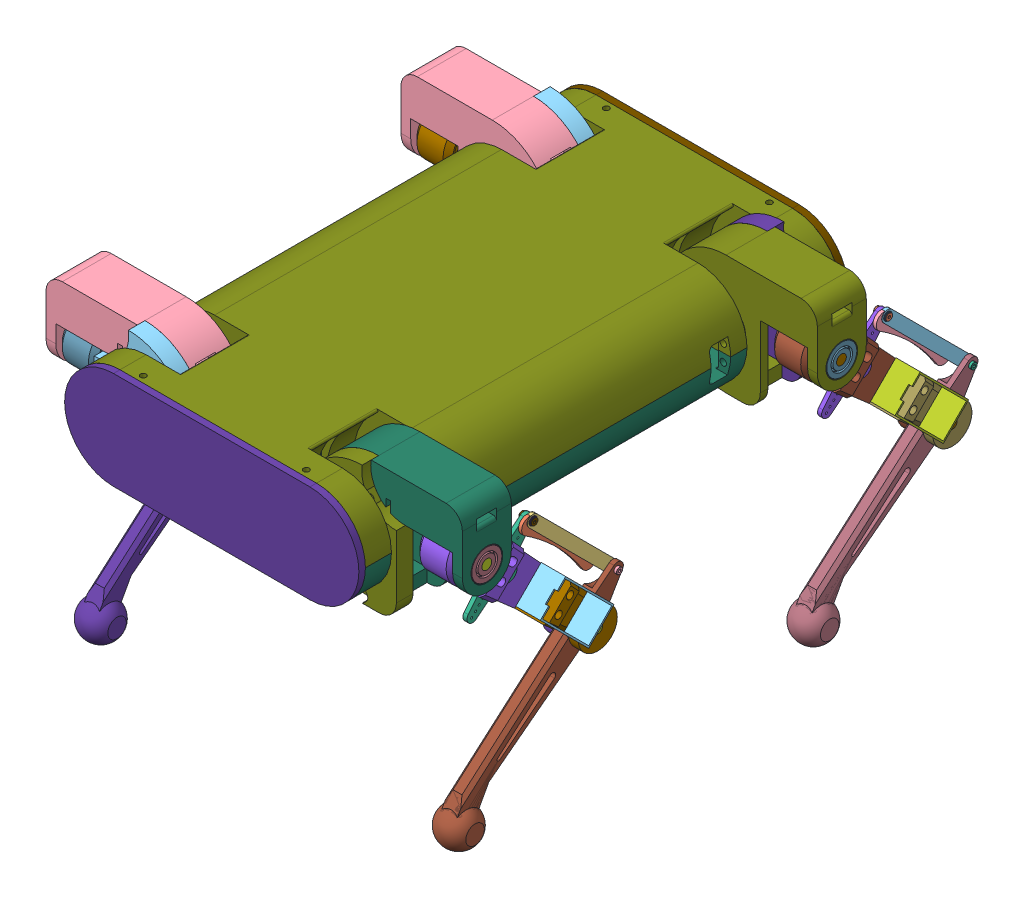
SolidWorks assembly Design, configuration Default. Lengths in mm.
Overall size (296.42 194.28 356.27).
132 component instances, 80 part files, 0 mates.
Components (placement in the parent):
- Design.STEP-1: Design.STEP [Default] at origin size (296.42 194.28 356.27)
  - legs.STEP-1: legs.STEP [Default] at origin size (296.42 194.28 346.24)
    - leg1.STEP-1: leg1.STEP [Default] at (-120.6897 -147.7213 110.0971) x (0 0 -1) z (1 0 0) size (128.74 194.28 113.16)
      - shoulder_joint.STEP-1: shoulder_joint.STEP [Default] at (0.6897 0.2213 10.9029) size (46.01 73.28 92.64)
        - Servo_00.STEP-1: Servo_00.STEP [Default] at (83.81 147 87) size (21 21 5.5)
          - Servo_00_horn.STEP-1: Servo_00_horn.STEP [Default] at (-145.7499 2.8989 -75.1177) x (-1 0 0) z (0 0 -1) size (21 21 5.5)
          - Servo_00-0.STEP-1: Servo_00-0.STEP [Default] at origin
        - Bearing 19mm.STEP-1: Bearing 19mm.STEP [Default] at (83.8 146.8 77.1) size (19 19 6)
        - Shaft 8mm.STEP-1: Shaft 8mm.STEP [Default] at (-17.7971 -1.7 -3.6029) x (0 0 -1) z (1 0 0) size (8 8 18)
        - shoulder_joint-1.STEP-1: shoulder_joint-1.STEP [Default] at origin size (30 73.28 92.64)
        - shoulder_joint-2.STEP-1: shoulder_joint-2.STEP [Default] at origin size (10.19 73.28 57.64)
      - upper_joint.STEP-1: upper_joint.STEP [Default] at origin size (112.4 102 49.52)
        - Servo_04_link.STEP-1: Servo_04_link.STEP [Default] at (84.861 148.6857 92.0002) size (55.54 55.54 12)
          - Bearing 5mm.STEP-1: Bearing 5mm.STEP [Default] at (-39.4979 -6.7113 -81.5973) size (5 5 1.32)
          - screw_nut M2 L60.STEP-1: screw_nut M2 L60.STEP [Default] at (-39.5148 -6.7145 -83.0127) x (-1 0 0) z (0 0 -1) size (4 4.62 8.04)
          - screw_nut M2 L100.STEP-1: screw_nut M2 L100.STEP [Default] at (9.0287 -55.2645 -76.5973) size (4 4.62 1.99)
          - Bearing 5mm.STEP-2: Bearing 5mm.STEP [Default] at (9.0584 -55.2504 -81.0973) size (5 5 1.32)
          - Servo_04_link-3.STEP-1: Servo_04_link-3.STEP [Default] at origin size (55.54 55.54 2)
          - Servo_04_link-4.STEP-1: Servo_04_link-4.STEP [Default] at origin size (3.8 3.8 12)
        - Servo_04.STEP-1: Servo_04.STEP [Default] at (82.1599 151.3869 92.0002) size (45.25 45.25 15)
        - Servo_04_horn.STEP-1: Servo_04_horn.STEP [Default] at (31.5884 184.987 92.0002) x (0.5 0.866025 0) z (0 0 1) size (53.36 19.42 8)
        - Shaft 6mm.STEP-1: Shaft 6mm.STEP [Default] at origin size (6 6 22)
        - Bearing 19mm.STEP-1: Bearing 19mm.STEP [Default] at (159.4897 72.0213 103.0029) size (19 19 6)
        - Shaft 6mm.STEP-2: Shaft 6mm.STEP [Default] at (75 -75 7) size (6 6 22)
        - upper_joint-5.STEP-1: upper_joint-5.STEP [Default] at origin size (102 102 24.5)
        - upper_joint-6.STEP-1: upper_joint-6.STEP [Default] at origin size (45.57 46.85 20.5)
      - stationary.STEP-1: stationary.STEP [Default] at (1 0 0) size (5.5 26.92 26.92)
        - Servo_08.STEP-1: Servo_08.STEP [Default] at (87.6897 148.3666 89.0358) size (5.5 26.92 26.92)
          - Servo_00_horn (1).STEP-1: Servo_00_horn (1).STEP [Default] at (-72.0856 -20.9487 17.5205) x (0 -0.34202 0.939693) z (-1 0 0) size (21 21 5.5)
          - Servo_08-7.STEP-1: Servo_08-7.STEP [Default] at origin
      - lower_joint.STEP-1: lower_joint.STEP [Default] at origin size (108.54 106.51 20)
    - leg0.STEP-1: leg0.STEP [Default] at (-120.6897 -147.7213 -107.5971) x (0 0 1) z (-1 0 0) size (117.89 194.28 113.16)
      - shoulder_joint(Mirror).STEP-1: shoulder_joint(Mirror).STEP [Default] at (0.6897 0.2213 -10.9029) size (46.01 73.28 92.64)
        - Servo_00(Mirror).STEP-1: Servo_00(Mirror).STEP [Default] at (83.81 147 -87) size (21 40.91 13.84)
          - Servo_00_horn(Mirror).STEP-1: Servo_00_horn(Mirror).STEP [Default] at (-145.7499 2.8989 75.1177) x (-1 0 0) z (0 0 -1) size (21 21 5.5)
          - Servo_00(Mirror)-8.STEP-1: Servo_00(Mirror)-8.STEP [Default] at origin size (0.04 0.01 0.01)
          - Servo_00(Mirror)-9.STEP-1: Servo_00(Mirror)-9.STEP [Default] at origin
        - Bearing 19mm(Mirror).STEP-1: Bearing 19mm(Mirror).STEP [Default] at (83.8 146.8 -77.1) size (19 19 6)
        - Shaft 8mm(Mirror).STEP-1: Shaft 8mm(Mirror).STEP [Default] at (-17.7971 -1.7 3.6029) x (0 0 1) z (-1 0 0) size (8 8 18)
        - shoulder_joint(Mirror)-10.STEP-1: shoulder_joint(Mirror)-10.STEP [Default] at origin size (30 73.28 92.64)
        - shoulder_joint(Mirror)-11.STEP-1: shoulder_joint(Mirror)-11.STEP [Default] at origin size (10.19 73.28 57.64)
      - stationary(Mirror).STEP-1: stationary(Mirror).STEP [Default] at (1 0 0) size (5.5 26.92 26.92)
        - Servo_08(Mirror).STEP-1: Servo_08(Mirror).STEP [Default] at (87.6897 148.3666 -89.0358) size (5.5 26.92 26.92)
          - Servo_00_horn (1)(Mirror).STEP-1: Servo_00_horn (1)(Mirror).STEP [Default] at (-72.0856 -20.9487 -17.5205) x (0 -0.34202 -0.939693) z (1 0 0) size (21 21 5.5)
          - Servo_08(Mirror)-12.STEP-1: Servo_08(Mirror)-12.STEP [Default] at origin
      - upper_joint_1.STEP-1: upper_joint_1.STEP [Default] at (0.1941 0 0) x (-1 0 0) z (0 0 -1) size (112.4 102 49.52)
        - Servo_04_link_1.STEP-1: Servo_04_link_1.STEP [Default] at (84.861 148.6857 92.0002) size (55.54 55.54 12)
          - Bearing 5mm.STEP-1: Bearing 5mm.STEP [Default] at (-39.4979 -6.7113 -81.5973) size (5 5 1.32)
          - screw_nut M2 L60.STEP-1: screw_nut M2 L60.STEP [Default] at (-39.5148 -6.7145 -83.0127) x (-1 0 0) z (0 0 -1) size (4 4.62 8.04)
          - screw_nut M2 L100.STEP-1: screw_nut M2 L100.STEP [Default] at (9.0287 -55.2645 -76.5973) size (4 4.62 1.99)
          - Bearing 5mm.STEP-2: Bearing 5mm.STEP [Default] at (9.0584 -55.2504 -81.0973) size (5 5 1.32)
          - Servo_04_link_1-13.STEP-1: Servo_04_link_1-13.STEP [Default] at origin size (55.54 55.54 2)
          - Servo_04_link_1-14.STEP-1: Servo_04_link_1-14.STEP [Default] at origin size (3.8 3.8 12)
        - Servo_04.STEP-1: Servo_04.STEP [Default] at (82.1599 151.3869 92.0002) size (45.25 45.25 15)
        - Servo_04_horn.STEP-1: Servo_04_horn.STEP [Default] at (31.5884 184.987 92.0002) x (0.5 0.866025 0) z (0 0 1) size (53.36 19.42 8)
        - Shaft 6mm.STEP-1: Shaft 6mm.STEP [Default] at origin size (6 6 22)
        - Bearing 19mm.STEP-1: Bearing 19mm.STEP [Default] at (159.4897 72.0213 103.0029) size (19 19 6)
        - Shaft 6mm.STEP-2: Shaft 6mm.STEP [Default] at (75 -75 7) size (6 6 22)
        - upper_joint_1-15.STEP-1: upper_joint_1-15.STEP [Default] at origin size (102 102 24.5)
        - upper_joint_1-16.STEP-1: upper_joint_1-16.STEP [Default] at origin size (45.57 46.85 20.5)
      - lower_joint.STEP-1: lower_joint.STEP [Default] at (0.1941 0 0) x (-1 0 0) z (0 0 -1) size (108.54 106.51 20)
    - leg3.STEP-1: leg3.STEP [Default] at (120.6897 -147.7213 110.0971) x (0 0 -1) z (1 0 0) size (128.74 194.28 113.16)
      - shoulder_joint(Mirror) (1).STEP-1: shoulder_joint(Mirror) (1).STEP [Default] at (0.6897 0.2213 -10.9029) size (46.01 73.28 92.64)
        - Servo_00(Mirror) (1).STEP-1: Servo_00(Mirror) (1).STEP [Default] at (83.81 147 -87) size (21 40.91 13.84)
          - Servo_00_horn(Mirror) (1).STEP-1: Servo_00_horn(Mirror) (1).STEP [Default] at (-145.7499 2.8989 75.1177) x (-1 0 0) z (0 0 -1) size (21 21 5.5)
          - Servo_00(Mirror) (1)-17.STEP-1: Servo_00(Mirror) (1)-17.STEP [Default] at origin size (0.04 0.01 0.01)
          - Servo_00(Mirror) (1)-18.STEP-1: Servo_00(Mirror) (1)-18.STEP [Default] at origin
        - Bearing 19mm(Mirror) (1).STEP-1: Bearing 19mm(Mirror) (1).STEP [Default] at (83.8 146.8 -77.1) size (19 19 6)
        - Shaft 8mm(Mirror) (1).STEP-1: Shaft 8mm(Mirror) (1).STEP [Default] at (-17.7971 -1.7 3.6029) x (0 0 1) z (-1 0 0) size (8 8 18)
        - shoulder_joint(Mirror) (1)-19.STEP-1: shoulder_joint(Mirror) (1)-19.STEP [Default] at origin size (30 73.28 92.64)
        - shoulder_joint(Mirror) (1)-20.STEP-1: shoulder_joint(Mirror) (1)-20.STEP [Default] at origin size (10.19 73.28 57.64)
      - upper_joint(Mirror) (1).STEP-1: upper_joint(Mirror) (1).STEP [Default] at origin size (112.4 102 49.52)
        - Servo_04_link(Mirror) (1).STEP-1: Servo_04_link(Mirror) (1).STEP [Default] at (84.861 148.6857 -92.0002) size (58.84 55.54 12)
          - Bearing 5mm(Mirror) (1).STEP-1: Bearing 5mm(Mirror) (1).STEP [Default] at (-39.4979 -6.7113 81.5973) size (5 5 1.32)
          - Bearing 5mm(Mirror) (1).STEP-2: Bearing 5mm(Mirror) (1).STEP [Default] at (9.0584 -55.2504 81.0973) size (5 5 1.32)
          - screw_nut M2 L60(Mirror) (1).STEP-1: screw_nut M2 L60(Mirror) (1).STEP [Default] at (-39.5148 -6.7145 83.0127) x (-1 0 0) z (0 0 -1) size (4 4.62 8.04)
          - screw_nut M2 L100(Mirror) (1).STEP-1: screw_nut M2 L100(Mirror) (1).STEP [Default] at (9.0287 -55.2645 76.5973) size (4 4.62 1.99)
          - Servo_04_link(Mirror) (1)-21.STEP-1: Servo_04_link(Mirror) (1)-21.STEP [Default] at origin size (46.34 46.34 2)
          - Servo_04_link(Mirror) (1)-22.STEP-1: Servo_04_link(Mirror) (1)-22.STEP [Default] at origin size (55.54 55.54 2)
          - Servo_04_link(Mirror) (1)-23.STEP-1: Servo_04_link(Mirror) (1)-23.STEP [Default] at origin size (3.8 3.8 12)
        - Servo_04(Mirror) (1).STEP-1: Servo_04(Mirror) (1).STEP [Default] at (82.1599 151.3869 -92.0002) size (45.25 45.25 15)
        - Servo_04_horn(Mirror) (1).STEP-1: Servo_04_horn(Mirror) (1).STEP [Default] at (31.5884 184.987 -92.0002) x (0.5 0.866025 0) z (0 0 1) size (53.36 19.42 8)
        - Shaft 6mm(Mirror) (1).STEP-1: Shaft 6mm(Mirror) (1).STEP [Default] at origin size (6 6 22)
        - Shaft 6mm(Mirror) (1).STEP-2: Shaft 6mm(Mirror) (1).STEP [Default] at (75 -75 -7) size (6 6 22)
        - Bearing 19mm(Mirror) (1).STEP-1: Bearing 19mm(Mirror) (1).STEP [Default] at (159.4897 72.0213 -103.0029) size (19 19 6)
        - upper_joint(Mirror) (1)-24.STEP-1: upper_joint(Mirror) (1)-24.STEP [Default] at origin size (102 102 24.5)
        - upper_joint(Mirror) (1)-25.STEP-1: upper_joint(Mirror) (1)-25.STEP [Default] at origin size (45.57 46.85 20.5)
      - stationary(Mirror) (1).STEP-1: stationary(Mirror) (1).STEP [Default] at (1 0 0) size (5.5 26.92 26.92)
        - Servo_08(Mirror) (1).STEP-1: Servo_08(Mirror) (1).STEP [Default] at (87.6897 148.3666 -89.0358) size (5.5 26.92 26.92)
          - Servo_00_horn (1)(Mirror) (1).STEP-1: Servo_00_horn (1)(Mirror) (1).STEP [Default] at (-72.0856 -20.9487 -17.5205) x (0 -0.34202 -0.939693) z (1 0 0) size (21 21 5.5)
          - Servo_08(Mirror) (1)-26.STEP-1: Servo_08(Mirror) (1)-26.STEP [Default] at origin
      - lower_joint(Mirror) (1).STEP-1: lower_joint(Mirror) (1).STEP [Default] at origin size (108.54 106.51 20)
    - leg4.STEP-1: leg4.STEP [Default] at (120.6897 -147.7213 -107.5971) x (0 0 1) z (-1 0 0) size (117.89 194.28 113.16)
      - shoulder_joint(Mirror)(Mirror).STEP-1: shoulder_joint(Mirror)(Mirror).STEP [Default] at (0.6897 0.2213 10.9029) size (46.01 73.28 92.64)
        - Servo_00(Mirror)(Mirror).STEP-1: Servo_00(Mirror)(Mirror).STEP [Default] at (83.81 147 87) size (21 40.91 13.84)
          - Servo_00_horn(Mirror)(Mirror).STEP-1: Servo_00_horn(Mirror)(Mirror).STEP [Default] at (-145.7499 2.8989 -75.1177) x (-1 0 0) z (0 0 -1) size (21 21 5.5)
          - Servo_00(Mirror)(Mirror)-27.STEP-1: Servo_00(Mirror)(Mirror)-27.STEP [Default] at origin size (0.04 0.01 0.01)
          - Servo_00(Mirror)(Mirror)-28.STEP-1: Servo_00(Mirror)(Mirror)-28.STEP [Default] at origin
        - Bearing 19mm(Mirror)(Mirror).STEP-1: Bearing 19mm(Mirror)(Mirror).STEP [Default] at (83.8 146.8 77.1) size (19 19 6)
        - Shaft 8mm(Mirror)(Mirror).STEP-1: Shaft 8mm(Mirror)(Mirror).STEP [Default] at (-17.7971 -1.7 -3.6029) x (0 0 -1) z (1 0 0) size (8 8 18)
        - shoulder_joint(Mirror)(Mirror)-29.STEP-1: shoulder_joint(Mirror)(Mirror)-29.STEP [Default] at origin size (30 73.28 92.64)
        - shoulder_joint(Mirror)(Mirror)-30.STEP-1: shoulder_joint(Mirror)(Mirror)-30.STEP [Default] at origin size (10.19 73.28 57.64)
      - stationary(Mirror)(Mirror).STEP-1: stationary(Mirror)(Mirror).STEP [Default] at (1 0 0) size (5.5 26.92 26.92)
        - Servo_08(Mirror)(Mirror).STEP-1: Servo_08(Mirror)(Mirror).STEP [Default] at (87.6897 148.3666 89.0358) size (5.5 26.92 26.92)
          - Servo_00_horn (1)(Mirror)(Mirror).STEP-1: Servo_00_horn (1)(Mirror)(Mirror).STEP [Default] at (-72.0856 -20.9487 17.5205) x (0 -0.34202 0.939693) z (-1 0 0) size (21 21 5.5)
          - Servo_08(Mirror)(Mirror)-31.STEP-1: Servo_08(Mirror)(Mirror)-31.STEP [Default] at origin
      - upper_joint(Mirror) (2).STEP-1: upper_joint(Mirror) (2).STEP [Default] at (0.1941 0 0) x (-1 0 0) z (0 0 -1) size (112.4 102 49.52)
        - Servo_04_link(Mirror) (2).STEP-1: Servo_04_link(Mirror) (2).STEP [Default] at (84.861 148.6857 -92.0002) size (58.84 55.54 12)
          - Bearing 5mm(Mirror) (2).STEP-1: Bearing 5mm(Mirror) (2).STEP [Default] at (-39.4979 -6.7113 81.5973) size (5 5 1.32)
          - Bearing 5mm(Mirror) (2).STEP-2: Bearing 5mm(Mirror) (2).STEP [Default] at (9.0584 -55.2504 81.0973) size (5 5 1.32)
          - screw_nut M2 L60(Mirror) (2).STEP-1: screw_nut M2 L60(Mirror) (2).STEP [Default] at (-39.5148 -6.7145 83.0127) x (-1 0 0) z (0 0 -1) size (4 4.62 8.04)
          - screw_nut M2 L100(Mirror) (2).STEP-1: screw_nut M2 L100(Mirror) (2).STEP [Default] at (9.0287 -55.2645 76.5973) size (4 4.62 1.99)
          - Servo_04_link(Mirror) (2)-32.STEP-1: Servo_04_link(Mirror) (2)-32.STEP [Default] at origin size (46.34 46.34 2)
          - Servo_04_link(Mirror) (2)-33.STEP-1: Servo_04_link(Mirror) (2)-33.STEP [Default] at origin size (55.54 55.54 2)
          - Servo_04_link(Mirror) (2)-34.STEP-1: Servo_04_link(Mirror) (2)-34.STEP [Default] at origin size (3.8 3.8 12)
        - Servo_04(Mirror) (2).STEP-1: Servo_04(Mirror) (2).STEP [Default] at (82.1599 151.3869 -92.0002) size (45.25 45.25 15)
        - Servo_04_horn(Mirror) (2).STEP-1: Servo_04_horn(Mirror) (2).STEP [Default] at (31.5884 184.987 -92.0002) x (0.5 0.866025 0) z (0 0 1) size (53.36 19.42 8)
        - Shaft 6mm(Mirror) (2).STEP-1: Shaft 6mm(Mirror) (2).STEP [Default] at origin size (6 6 22)
        - Shaft 6mm(Mirror) (2).STEP-2: Shaft 6mm(Mirror) (2).STEP [Default] at (75 -75 -7) size (6 6 22)
        - Bearing 19mm(Mirror) (2).STEP-1: Bearing 19mm(Mirror) (2).STEP [Default] at (159.4897 72.0213 -103.0029) size (19 19 6)
        - upper_joint(Mirror) (2)-35.STEP-1: upper_joint(Mirror) (2)-35.STEP [Default] at origin size (102 102 24.5)
        - upper_joint(Mirror) (2)-36.STEP-1: upper_joint(Mirror) (2)-36.STEP [Default] at origin size (45.57 46.85 20.5)
      - lower_joint(Mirror) (2).STEP-1: lower_joint(Mirror) (2).STEP [Default] at (0.1941 0 0) x (-1 0 0) z (0 0 -1) size (108.54 106.51 20)
  - body.STEP-1: body.STEP [Default] at (0.2452 0.2562 1.1354) size (180.49 60 300)
    - bearing.STEP-1: bearing.STEP [Default] at (-71.7 0 134) size (22 22 6)
    - bearing.STEP-2: bearing.STEP [Default] at (71.8 0 134) size (22 22 6)
    - bearing.STEP-3: bearing.STEP [Default] at (-71.7 0 -133) size (22 22 6)
    - bearing.STEP-4: bearing.STEP [Default] at (71.8 0 -133) size (22 22 6)
    - body-37.STEP-1: body-37.STEP [Default] at origin size (180.49 44.45 292)
    - body-38.STEP-1: body-38.STEP [Default] at origin size (180.49 30 292)
    - body-39.STEP-1: body-39.STEP [Default] at origin size (180.49 60 11)
    - body-40.STEP-1: body-40.STEP [Default] at origin size (180.49 60 11)
